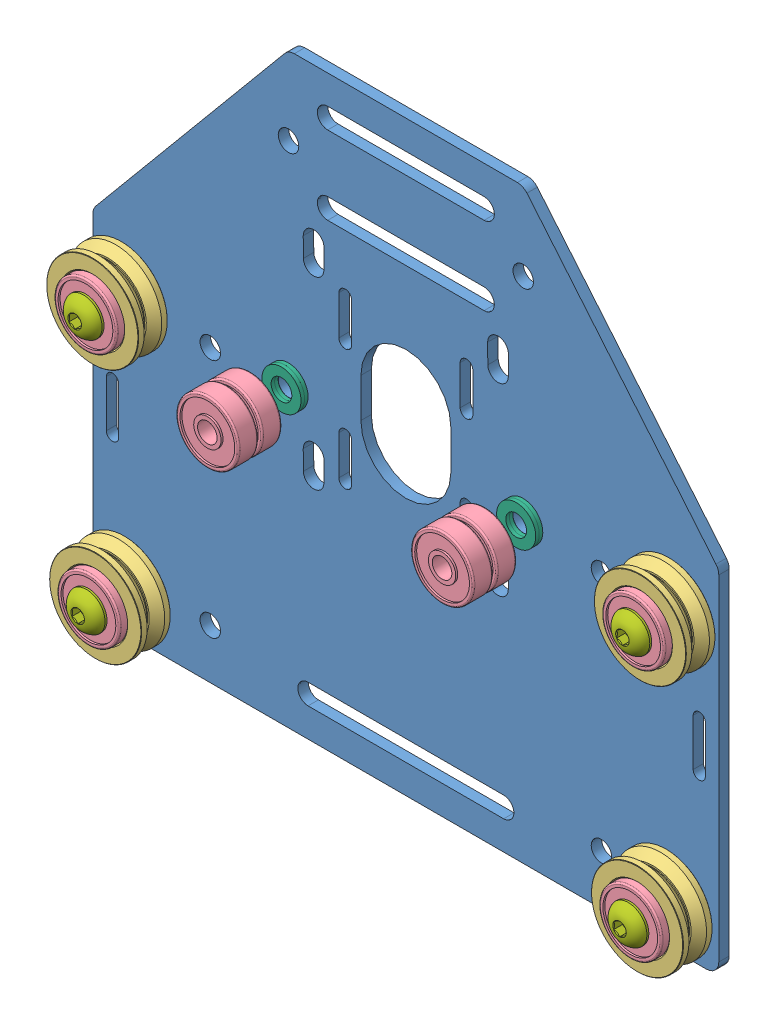
SolidWorks assembly plate_assembly_stacked, configuration Default. Lengths in mm.
Overall size (164.61 150 32.91).
57 component instances, 11 part files, 66 mates.
Components (placement in the parent):
- 26029-01-1: 26029-01 [Default] at origin size (160 150 2.66)
- B18033-1: B18033 [Default] at (160.9384 20.9044 -3.9878) x (-0.352192 0.935928 0) z (0 0 1) size (9.18 7.95 5.26)
- B18033-2: B18033 [Default] at (20.9384 20.9044 -3.9878) x (-0.283832 -0.958874 0) z (0 0 1) size (9.18 7.95 5.26)
- 25203-02-1: 25203-02 [Default] at (20.9384 85.5044 9.0568) x (0.995036 -0.099517 0) z (-0.099517 -0.995036 0) size (23.5 11 23.5)
  - 25202-01-1: 25202-01 [Default] at origin size (23.5 7.5 23.5)
  - 25196-01-1: 25196-01 [Default] at (0 -3 0) x (0.224141 0 -0.974557) z (-0.974557 0 -0.224141) size (16 5 16)
  - 25201-01-1: 25201-01 [Default] at (0 -0.5 0) x (0.992075 0 -0.125646) z (0.125646 0 0.992075) size (10 1 10)
  - 25196-01-2: 25196-01 [Default] at (0 3 0) x (-0.996407 0 -0.084695) z (-0.084695 0 0.996407) size (16 5 16)
- 25287-02-1: 25287-02 [Default] at (20.9384 85.5044 3.5568) size (10 10 0.9)
- 91239A233-1: 91239A233 [Default] at (20.9384 85.5044 -5.4432) x (1 0 0) z (0 0 -1) size (9.5 9.5 22.91)
- 25287-02-2: 25287-02 [Default] at (160.2015 20.6271 2.6568) x (-0.923728 -0.383049 0) z (0 0 -1) size (10 10 0.9)
- 25284-02-1: 25284-02 [Default] at (20.9384 85.5044 -2.9) x (1 0 0) z (0 -1 0) size (8 4.29 9.24)
- 25287-02-3: 25287-02 [Default] at (160.9384 85.5044 0) size (10 10 0.9)
- 25287-02-4: 25287-02 [Default] at (160.9384 85.5044 3.5568) size (10 10 0.9)
- 25287-02-5: 25287-02 [Default] at (21.6934 20.6809 2.6568) x (-0.923728 -0.383049 0) z (0 0 -1) size (10 10 0.9)
- 25287-02-6: 25287-02 [Default] at (20.9384 85.5044 -0.9) x (1 0 0) z (0 0 -1) size (10 10 0.9)
- 91239A233-2: 91239A233 [Default] at (21.6934 20.6809 -5.4432) x (1 0 0) z (0 0 -1) size (9.5 9.5 22.91)
- 25203-02-2: 25203-02 [Default] at (21.6934 20.6809 9.0568) x (1 0 0) z (0 1 0) size (23.5 11 23.5)
  - 25202-01-1: 25202-01 [Default] at origin size (23.5 7.5 23.5)
  - 25196-01-1: 25196-01 [Default] at (0 -3 0) x (0.224141 0 -0.974557) z (-0.974557 0 -0.224141) size (16 5 16)
  - 25201-01-1: 25201-01 [Default] at (0 -0.5 0) x (0.992075 0 -0.125646) z (0.125646 0 0.992075) size (10 1 10)
  - 25196-01-2: 25196-01 [Default] at (0 3 0) x (-0.996407 0 -0.084695) z (-0.084695 0 0.996407) size (16 5 16)
- 91239A233-3: 91239A233 [Default] at (160.2015 20.6271 -5.4432) x (1 0 0) z (0 0 -1) size (9.5 9.5 22.91)
- 25203-02-3: 25203-02 [Default] at (160.2015 20.6271 9.0568) x (1 0 0) z (0 1 0) size (23.5 11 23.5)
  - 25202-01-1: 25202-01 [Default] at origin size (23.5 7.5 23.5)
  - 25196-01-1: 25196-01 [Default] at (0 -3 0) x (0.224141 0 -0.974557) z (-0.974557 0 -0.224141) size (16 5 16)
  - 25201-01-1: 25201-01 [Default] at (0 -0.5 0) x (0.992075 0 -0.125646) z (0.125646 0 0.992075) size (10 1 10)
  - 25196-01-2: 25196-01 [Default] at (0 3 0) x (-0.996407 0 -0.084695) z (-0.084695 0 0.996407) size (16 5 16)
- 91239A233-4: 91239A233 [Default] at (160.9384 85.5044 -5.4432) x (1 0 0) z (0 0 -1) size (9.5 9.5 22.91)
- 25203-02-4: 25203-02 [Default] at (160.9384 85.5044 9.0568) x (1 0 0) z (0 -1 0) size (23.5 11 23.5)
  - 25202-01-1: 25202-01 [Default] at origin size (23.5 7.5 23.5)
  - 25196-01-1: 25196-01 [Default] at (0 -3 0) x (0.224141 0 -0.974557) z (-0.974557 0 -0.224141) size (16 5 16)
  - 25201-01-1: 25201-01 [Default] at (0 -0.5 0) x (0.992075 0 -0.125646) z (0.125646 0 0.992075) size (10 1 10)
  - 25196-01-2: 25196-01 [Default] at (0 3 0) x (-0.996407 0 -0.084695) z (-0.084695 0 0.996407) size (16 5 16)
- 25284-02-2: 25284-02 [Default] at (160.9384 85.5044 -2.9) x (0.037474 -0.999298 0) z (-0.999298 -0.037474 0) size (8 4.29 9.24)
- 25197-02-1: 25197-02 [Default] at (128.9783 132.3034 54.0684) x (0 0 -1) z (-0.954972 -0.296697 0) size (12.6 21 21)
  - 25201-01-1: 25201-01 [Default] at (36.6716 43.7387 22.0081) x (0 1 0) z (0 0 1) size (10 1 10)
  - 25196-01-1: 25196-01 [Default] at (39.1716 43.7387 22.0081) x (0 1 0) z (0 0 1) size (16 5 16)
  - 25196-01-2: 25196-01 [Default] at (33.1716 43.7387 22.0081) x (0 1 0) z (0 0 1) size (16 5 16)
  - 25197-01-1: 25197-01 [Default] at (34.6716 43.7387 22.0081) size (11.2 21 21)
- 25197-02-2: 25197-02 [Default] at (57.254 35.1797 54.0684) x (0 0 -1) z (0.92458 0.380987 0) size (12.6 21 21)
  - 25201-01-1: 25201-01 [Default] at (36.6716 43.7387 22.0081) x (0 1 0) z (0 0 1) size (10 1 10)
  - 25196-01-1: 25196-01 [Default] at (39.1716 43.7387 22.0081) x (0 1 0) z (0 0 1) size (16 5 16)
  - 25196-01-2: 25196-01 [Default] at (33.1716 43.7387 22.0081) x (0 1 0) z (0 0 1) size (16 5 16)
  - 25197-01-1: 25197-01 [Default] at (34.6716 43.7387 22.0081) size (11.2 21 21)
- 25286-05-1: 25286-05 [Default] at (120.9384 84.0044 -6.6032) x (-0.651947 -0.758265 0) z (0 0 -1) size (9.5 9.5 32.91)
- 25287-02-7: 25287-02 [Default] at (120.9384 84.0044 0) size (10 10 0.9)
- 25284-02-3: 25284-02 [Default] at (120.9384 84.0044 -2.9) x (0.037474 -0.999298 0) z (-0.999298 -0.037474 0) size (8 4.29 9.24)
- 25286-05-2: 25286-05 [Default] at (60.9384 84.0044 -6.6032) x (0.940642 0.3394 0) z (0 0 -1) size (9.5 9.5 32.91)
- 25284-02-4: 25284-02 [Default] at (60.9384 84.0044 -2.9) x (-0.037474 0.999298 0) z (-0.999298 -0.037474 0) size (8 4.29 9.24)
- 25287-02-8: 25287-02 [Default] at (60.9384 84.0044 0) x (-0.99589 0.090569 0) z (0 0 1) size (10 10 0.9)
- 25312-14-1: 25312-14 [Default] at (60.9384 84.0044 4.4568) x (-0.162265 0.986747 0) z (0 0 1) size (9.53 9.53 7.94)
- 25312-14-2: 25312-14 [Default] at (120.9384 84.0044 12.3968) x (0.519042 -0.854749 0) z (0 0 -1) size (9.53 9.53 7.94)
- 25287-02-9: 25287-02 [Default] at (60.9384 84.0044 2.6568) x (0.999419 -0.034095 0) z (0 0 -1) size (10 10 0.9)
- 25287-02-10: 25287-02 [Default] at (60.9384 84.0044 4.4568) x (0.999419 0.034095 0) z (0 0 1) size (10 10 0.9)
- 25287-02-11: 25287-02 [Default] at (120.9384 84.0044 3.5568) x (0.999419 -0.034095 0) z (0 0 -1) size (10 10 0.9)
- 25287-02-12: 25287-02 [Default] at (120.9384 84.0044 2.6568) x (0.999419 -0.034095 0) z (0 0 -1) size (10 10 0.9)
Mates (geometry in assembly coordinates):
- Concentric1: concentric aligned: cylinder of 26029-01-1 through (20.9384 85.5044 2.6568) axis (0 0 -1) radius 2.625; cylinder of 91239A233-1 through (20.9384 85.5044 17.3068) axis (0 0 -1) radius 4.75
- Concentric2: concentric aligned: cylinder of 26029-01-1 through (60.9384 84.0044 2.6568) axis (0 0 -1) radius 2.625; cylinder of 25286-05-2 through (60.9384 84.0044 26.1468) axis (0 0 -1) radius 4.75
- Concentric3: concentric aligned: cylinder of 26029-01-1 through (120.9384 84.0044 2.6568) axis (0 0 -1) radius 2.625; cylinder of 25286-05-1 through (120.9384 84.0044 26.1468) axis (0 0 -1) radius 4.75
- Concentric4: concentric: cylinder of 26029-01-1 through (160.9384 85.5044 2.6568) axis (0 0 -1) radius 2.625; cylinder of 91239A233-4 through (160.9384 85.5044 17.3068) axis (0 0 -1) radius 4.75
- Concentric5: concentric anti-aligned: cylinder of 26029-01-1 through (20.9384 85.5044 2.6568) axis (0 0 -1) radius 2.625; cylinder of 25287-02-1 through (20.9384 85.5044 2.6568) axis (0 0 1) radius 2.65
- Concentric6: concentric aligned: cylinder of 26029-01-1 through (60.9384 84.0044 2.6568) axis (0 0 -1) radius 2.625; cylinder of 25287-02-9 through (60.9384 84.0044 3.5568) axis (0 0 -1) radius 2.65
- Concentric7: concentric anti-aligned: cylinder of 26029-01-1 through (60.9384 84.0044 2.6568) axis (0 0 -1) radius 2.625; cylinder of 25287-02-10 through (60.9384 84.0044 3.5568) axis (0 0 1) radius 2.65
- Concentric8: concentric aligned: cylinder of 26029-01-1 through (120.9384 84.0044 2.6568) axis (0 0 -1) radius 2.625; cylinder of 25287-02-11 through (120.9384 84.0044 4.4568) axis (0 0 -1) radius 2.65
- Concentric9: concentric aligned: cylinder of 26029-01-1 through (120.9384 84.0044 2.6568) axis (0 0 -1) radius 2.625; cylinder of 25287-02-12 through (120.9384 84.0044 3.5568) axis (0 0 -1) radius 2.65
- Concentric10: concentric aligned: cylinder of 26029-01-1 through (160.9384 85.5044 2.6568) axis (0 0 -1) radius 2.625; circle of 25287-02-4
- Concentric11: concentric anti-aligned: cylinder of 91239A233-2 through (21.6934 20.6809 17.3068) axis (0 0 -1) radius 4.75; cylinder of B18033-2 through (21.6934 20.6809 -11.9635) axis (0 0 1) radius 2.0701
- Concentric12: concentric anti-aligned: cylinder of 25287-02-5 through (21.6934 20.6809 3.5568) axis (0 0 -1) radius 2.65; cylinder of B18033-2 through (21.6934 20.6809 -11.9635) axis (0 0 1) radius 2.0701
- Concentric13: concentric aligned: cylinder of 91239A233-2 through (21.6934 20.6809 17.3068) axis (0 0 -1) radius 4.75; cylinder of 25203-02-2/25196-01-1 through (21.6934 20.6809 14.8068) axis (0 0 -1) radius 2.5
- Concentric14: concentric anti-aligned: cylinder of 91239A233-3 through (160.2015 20.6271 17.3068) axis (0 0 -1) radius 4.75; cylinder of B18033-1 through (160.2015 20.6271 -11.9635) axis (0 0 1) radius 2.0701
- Concentric15: concentric anti-aligned: cylinder of 25287-02-2 through (160.2015 20.6271 3.5568) axis (0 0 -1) radius 2.65; cylinder of B18033-1 through (160.2015 20.6271 -11.9635) axis (0 0 1) radius 2.0701
- Concentric16: concentric aligned: cylinder of 91239A233-3 through (160.2015 20.6271 17.3068) axis (0 0 -1) radius 4.75; cylinder of 25203-02-3/25196-01-1 through (160.2015 20.6271 14.8068) axis (0 0 -1) radius 2.5
- Concentric17: concentric anti-aligned: cylinder of 91239A233-4 through (160.9384 85.5044 17.3068) axis (0 0 -1) radius 4.75; cylinder of 25203-02-4/25196-01-2 through (160.9384 85.5044 9.3068) axis (0 0 1) radius 2.5
- Concentric18: concentric: cylinder of 25197-02-1/25196-01-2 through (120.9384 84.0044 23.6468) axis (0 0 -1) radius 2.5; cylinder of 25286-05-1 through (120.9384 84.0044 26.1468) axis (0 0 -1) radius 4.75
- Concentric19: concentric: cylinder of 25197-02-2/25196-01-2 through (60.9384 84.0044 23.6468) axis (0 0 -1) radius 2.5; cylinder of 25286-05-2 through (60.9384 84.0044 26.1468) axis (0 0 -1) radius 4.75
- Concentric20: concentric anti-aligned: cylinder of 25203-02-1/25196-01-2 through (20.9384 85.5044 9.3068) axis (0 0 1) radius 2.5; cylinder of 91239A233-1 through (20.9384 85.5044 17.3068) axis (0 0 -1) radius 4.75
- Concentric21: concentric anti-aligned: cylinder of 26029-01-1 through (160.9384 85.5044 2.6568) axis (0 0 -1) radius 2.625; cylinder of 25287-02-3 through (160.9384 85.5044 -0.9) axis (0 0 1) radius 2.65
- Concentric22: concentric anti-aligned: circle of 25284-02-2; cylinder of 26029-01-1 through (160.9384 85.5044 2.6568) axis (0 0 -1) radius 2.625
- Concentric23: concentric anti-aligned: cylinder of 26029-01-1 through (120.9384 84.0044 2.6568) axis (0 0 -1) radius 2.625; cylinder of 25287-02-7 through (120.9384 84.0044 -0.9) axis (0 0 1) radius 2.65
- Concentric24: concentric anti-aligned: cylinder of 26029-01-1 through (120.9384 84.0044 2.6568) axis (0 0 -1) radius 2.625; circle of 25284-02-3
- Concentric25: concentric aligned: cylinder of 26029-01-1 through (60.9384 84.0044 2.6568) axis (0 0 -1) radius 2.625; circle of 25284-02-4
- Concentric26: concentric anti-aligned: cylinder of 26029-01-1 through (60.9384 84.0044 2.6568) axis (0 0 -1) radius 2.625; cylinder of 25287-02-8 through (60.9384 84.0044 -0.9) axis (0 0 1) radius 2.65
- Concentric27: concentric aligned: cylinder of 26029-01-1 through (20.9384 85.5044 2.6568) axis (0 0 -1) radius 2.625; cylinder of 25287-02-6 through (20.9384 85.5044 0) axis (0 0 -1) radius 2.65
- Concentric28: concentric anti-aligned: cylinder of 26029-01-1 through (20.9384 85.5044 2.6568) axis (0 0 -1) radius 2.625; circle of 25284-02-1
- Concentric29: concentric anti-aligned: cylinder of 26029-01-1 through (20.9384 20.9044 2.6568) axis (0 0 -1) radius 3.57; cylinder of B18033-2 through (20.9384 20.9044 0) axis (0 0 1) radius 3.556
- Concentric30: concentric anti-aligned: cylinder of 26029-01-1 through (160.9384 20.9044 2.6568) axis (0 0 -1) radius 3.57; cylinder of B18033-1 through (160.9384 20.9044 0) axis (0 0 1) radius 3.556
- Coincident1: coincident anti-aligned: plane of 25287-02-3 through (160.9384 85.5044 -0.9) normal (0 0 -1); plane of 25284-02-2 through (165.554 85.6775 -0.9) normal (0 0 1)
- Coincident2: coincident anti-aligned: plane of 25287-02-7 through (120.9384 84.0044 -0.9) normal (0 0 -1); plane of 25284-02-3 through (125.554 84.1775 -0.9) normal (0 0 1)
- Coincident3: coincident anti-aligned: plane of 25284-02-4 through (65.554 84.1775 -0.9) normal (0 0 1); plane of 25287-02-8 through (60.9384 84.0044 -0.9) normal (0 0 -1)
- Coincident4: coincident anti-aligned: plane of 25284-02-1 through (20.9384 90.1232 -0.9) normal (0 0 1); plane of 25287-02-6 through (20.9384 85.5044 -0.9) normal (0 0 -1)
- Coincident5: coincident anti-aligned: plane of 26029-01-1 through (90.9384 72.6493 0) normal (0 0 -1); plane of 25287-02-6 through (20.9384 85.5044 0) normal (0 0 1)
- Coincident6: coincident anti-aligned: plane of 26029-01-1 through (90.9384 72.6493 0) normal (0 0 -1); plane of 25287-02-8 through (60.9384 84.0044 0) normal (0 0 1)
- Coincident7: coincident anti-aligned: plane of 26029-01-1 through (90.9384 72.6493 0) normal (0 0 -1); plane of 25287-02-7 through (120.9384 84.0044 0) normal (0 0 1)
- Coincident8: coincident anti-aligned: plane of 26029-01-1 through (90.9384 72.6493 0) normal (0 0 -1); plane of 25287-02-3 through (160.9384 85.5044 0) normal (0 0 1)
- Coincident9: coincident anti-aligned: plane of 26029-01-1 through (90.9384 72.6493 0) normal (0 0 -1); plane of B18033-1 through (160.9384 20.9044 0) normal (0 0 1)
- Coincident10: coincident anti-aligned: plane of 26029-01-1 through (90.9384 72.6493 0) normal (0 0 -1); plane of B18033-2 through (20.9384 20.9044 0) normal (0 0 1)
- Coincident11: coincident anti-aligned: plane of 25203-02-1/25196-01-1 through (20.9384 85.5044 3.5568) normal (0 0 -1); plane of 25287-02-1 through (20.9384 85.5044 3.5568) normal (0 0 1)
- Coincident12: coincident anti-aligned: plane of 25203-02-1/25196-01-2 through (20.9384 85.5044 14.5568) normal (0 0 1); plane of 91239A233-1 through (20.9384 85.5044 14.5568) normal (0 0 -1)
- Coincident13: coincident anti-aligned: plane of 25197-02-2/25196-01-2 through (60.9384 84.0044 23.3968) normal (0 0 1); plane of 25286-05-2 through (60.9384 84.0044 23.3968) normal (0 0 -1)
- Coincident14: coincident anti-aligned: plane of 25197-02-2/25196-01-1 through (60.9384 84.0044 12.3968) normal (0 0 -1); plane of 25312-14-1 through (60.9384 84.0044 12.3968) normal (0 0 1)
- Coincident15: coincident anti-aligned: plane of 25312-14-1 through (60.9384 84.0044 4.4568) normal (0 0 -1); plane of 25287-02-10 through (60.9384 84.0044 4.4568) normal (0 0 1)
- Concentric31: concentric aligned: cylinder of 25312-14-1 through (60.9384 84.0044 4.4568) axis (0 0 1) radius 4.765; cylinder of 25287-02-10 through (60.9384 84.0044 3.5568) axis (0 0 1) radius 5
- Coincident16: coincident anti-aligned: plane of 25287-02-9 through (60.9384 84.0044 3.5568) normal (0 0 1); plane of 25287-02-10 through (60.9384 84.0044 3.5568) normal (0 0 -1)
- Coincident17: coincident anti-aligned: plane of 26029-01-1 through (90.9384 72.6493 2.6568) normal (0 0 1); plane of 25287-02-9 through (60.9384 84.0044 2.6568) normal (0 0 -1)
- Coincident18: coincident anti-aligned: plane of 26029-01-1 through (90.9384 72.6493 2.6568) normal (0 0 1); plane of 25287-02-1 through (20.9384 85.5044 2.6568) normal (0 0 -1)
- Coincident19: coincident anti-aligned: plane of 25287-02-11 through (120.9384 84.0044 3.5568) normal (0 0 -1); plane of 25287-02-12 through (120.9384 84.0044 3.5568) normal (0 0 1)
- Coincident20: coincident anti-aligned: plane of 25312-14-2 through (120.9384 84.0044 4.4568) normal (0 0 -1); plane of 25287-02-11 through (120.9384 84.0044 4.4568) normal (0 0 1)
- Concentric32: concentric aligned: cylinder of 25286-05-1 through (120.9384 84.0044 26.1468) axis (0 0 -1) radius 4.75; cylinder of 25312-14-2 through (120.9384 84.0044 12.3968) axis (0 0 -1) radius 2.78
- Coincident21: coincident anti-aligned: plane of 25197-02-1/25196-01-1 through (120.9384 84.0044 12.3968) normal (0 0 -1); plane of 25312-14-2 through (120.9384 84.0044 12.3968) normal (0 0 1)
- Coincident22: coincident anti-aligned: plane of 25197-02-1/25196-01-2 through (120.9384 84.0044 23.3968) normal (0 0 1); plane of 25286-05-1 through (120.9384 84.0044 23.3968) normal (0 0 -1)
- Coincident23: coincident anti-aligned: plane of 26029-01-1 through (90.9384 72.6493 2.6568) normal (0 0 1); plane of 25287-02-12 through (120.9384 84.0044 2.6568) normal (0 0 -1)
- Coincident24: coincident anti-aligned: plane of 25287-02-4 through (160.9384 85.5044 3.5568) normal (0 0 1); plane of 25203-02-4/25196-01-1 through (160.9384 85.5044 3.5568) normal (0 0 -1)
- Coincident25: coincident anti-aligned: plane of 91239A233-4 through (160.9384 85.5044 14.5568) normal (0 0 -1); plane of 25203-02-4/25196-01-2 through (160.9384 85.5044 14.5568) normal (0 0 1)
- Coincident26: coincident anti-aligned: plane of 26029-01-1 through (90.9384 72.6493 2.6568) normal (0 0 1); plane of 25287-02-4 through (160.9384 85.5044 2.6568) normal (0 0 -1)
- Coincident27: coincident anti-aligned: plane of 25287-02-2 through (160.2015 20.6271 3.5568) normal (0 0 1); plane of 25203-02-3/25196-01-2 through (160.2015 20.6271 3.5568) normal (0 0 -1)
- Coincident28: coincident anti-aligned: plane of 91239A233-3 through (160.2015 20.6271 14.5568) normal (0 0 -1); plane of 25203-02-3/25196-01-1 through (160.2015 20.6271 14.5568) normal (0 0 1)
- Coincident29: coincident anti-aligned: plane of 26029-01-1 through (90.9384 72.6493 2.6568) normal (0 0 1); plane of 25287-02-2 through (160.2015 20.6271 2.6568) normal (0 0 -1)
- Coincident30: coincident anti-aligned: plane of 91239A233-2 through (21.6934 20.6809 14.5568) normal (0 0 -1); plane of 25203-02-2/25196-01-1 through (21.6934 20.6809 14.5568) normal (0 0 1)
- Coincident31: coincident anti-aligned: plane of 25287-02-5 through (21.6934 20.6809 3.5568) normal (0 0 1); plane of 25203-02-2/25196-01-2 through (21.6934 20.6809 3.5568) normal (0 0 -1)
- Coincident32: coincident anti-aligned: plane of 26029-01-1 through (90.9384 72.6493 2.6568) normal (0 0 1); plane of 25287-02-5 through (21.6934 20.6809 2.6568) normal (0 0 -1)
- Coincident33: coincident aligned: plane of 25284-02-2 through (158.7805 81.4207 -0.9) normal (0.037474 -0.999298 0); plane of 25284-02-3 through (118.7805 79.9207 -0.9) normal (0.037474 -0.999298 0)
- Parallel1: parallel aligned: plane of 25284-02-3 through (118.7805 79.9207 -0.9) normal (0.037474 -0.999298 0); plane of 25284-02-4 through (63.3961 80.0938 -4.9) normal (0.037474 -0.999298 0)
